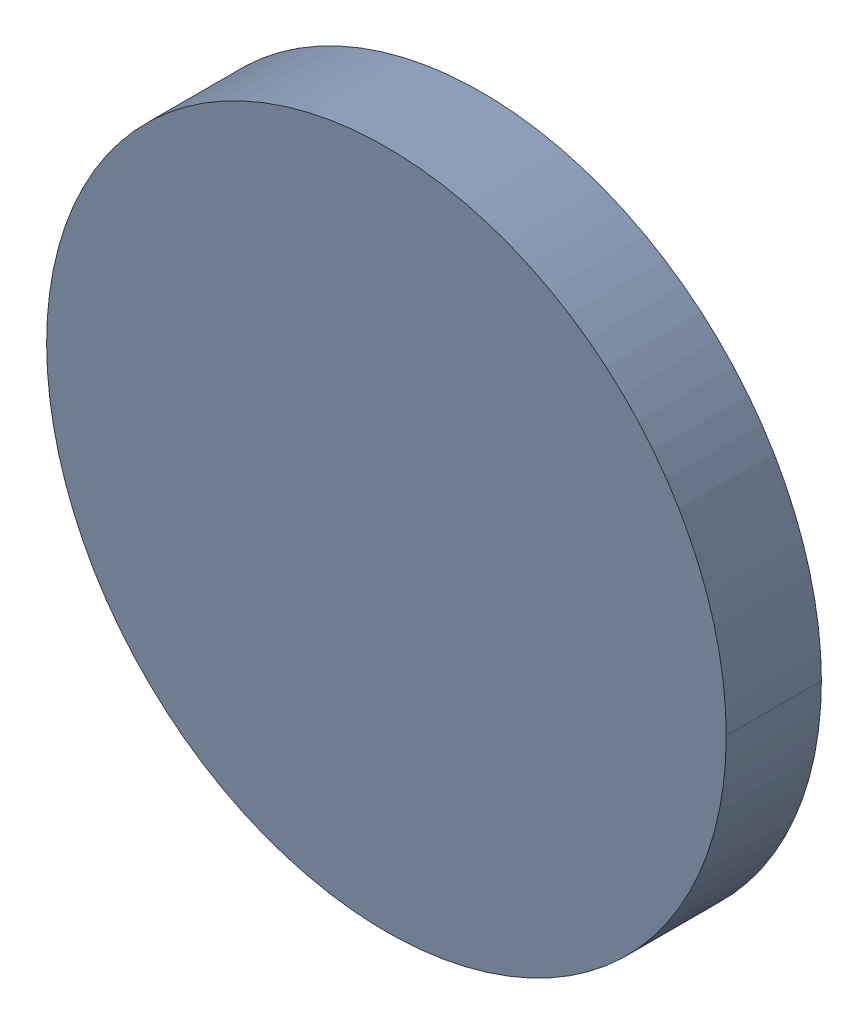
SolidWorks assembly Track (29mm,40mm)(29mm,40mm) on Top Layer, configuration Predeterminado. Lengths in mm.
Overall size (0.25 0.25 0.04).
2 component instances, 1 part files, 0 mates.
Components (placement in the parent):
- Track (29mm,40mm)(29mm,40mm) on Top Layer-1-1: Track (29mm,40mm)(29mm,40mm) on Top Layer-1 [Predeterminado] at (-68.317 -44.187 -0.0457) size (0.25 0.25 0.04)
  - Track (29mm,40mm)(29mm,40mm) on Top Layer-Part-1-1: Track (29mm,40mm)(29mm,40mm) on Top Layer-Part-1 [Predeterminado] at origin size (0.25 0.25 0.04)
